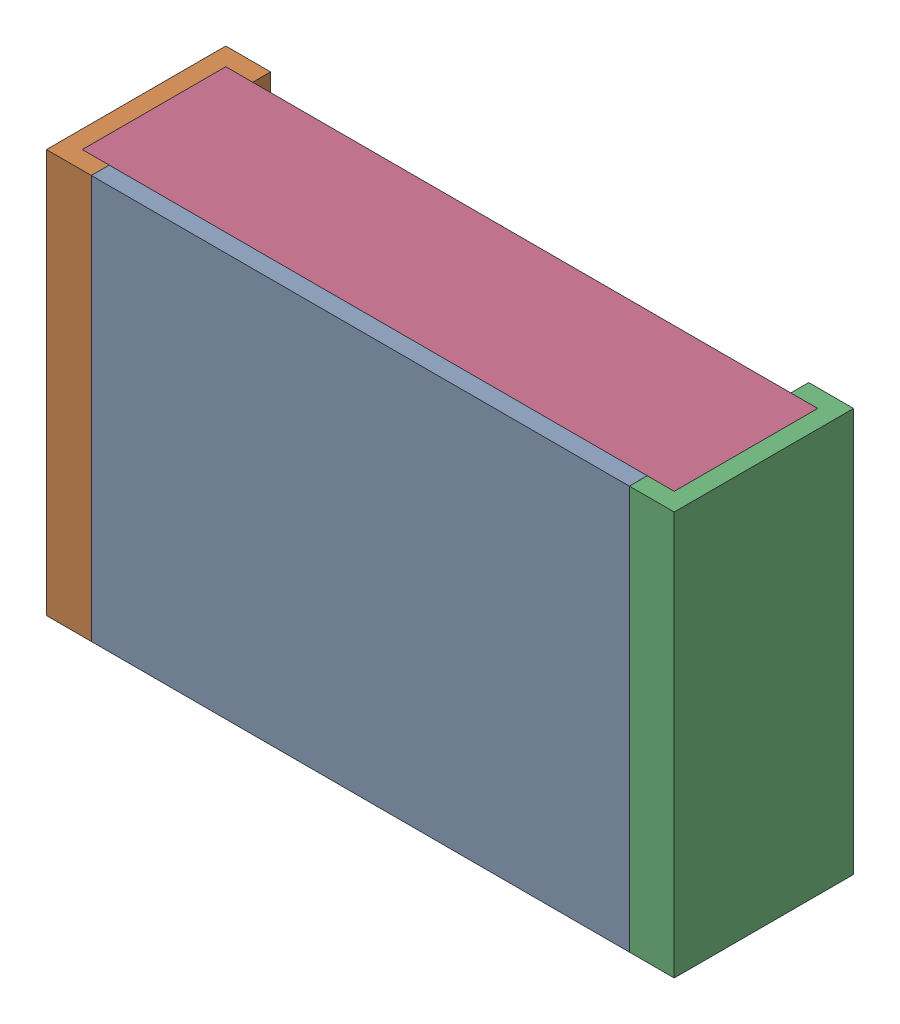
SolidWorks assembly RESC2012X06N.step, configuration По умолчанию. Lengths in mm.
Overall size (2.1 1.35 0.6).
4 component instances, 3 part files, 0 mates.
Components (placement in the parent):
- RESC2012X06N.step-Part-1-1: RESC2012X06N.step-Part-1 [По умолчанию] at (-0.9 -0.675 0.54) size (1.8 1.35 0.06)
- RESC2012X06N.step-Part-2-1: RESC2012X06N.step-Part-2 [По умолчанию] at (-1.05 -0.675 0) size (0.15 1.35 0.6)
- RESC2012X06N.step-Part-2-2: RESC2012X06N.step-Part-2 [По умолчанию] at (1.05 0.675 0) x (-1 0 0) z (0 0 1) size (0.15 1.35 0.6)
- RESC2012X06N.step-Part-3-1: RESC2012X06N.step-Part-3 [По умолчанию] at (-1.05 -0.675 0) size (1.98 1.35 0.48)
